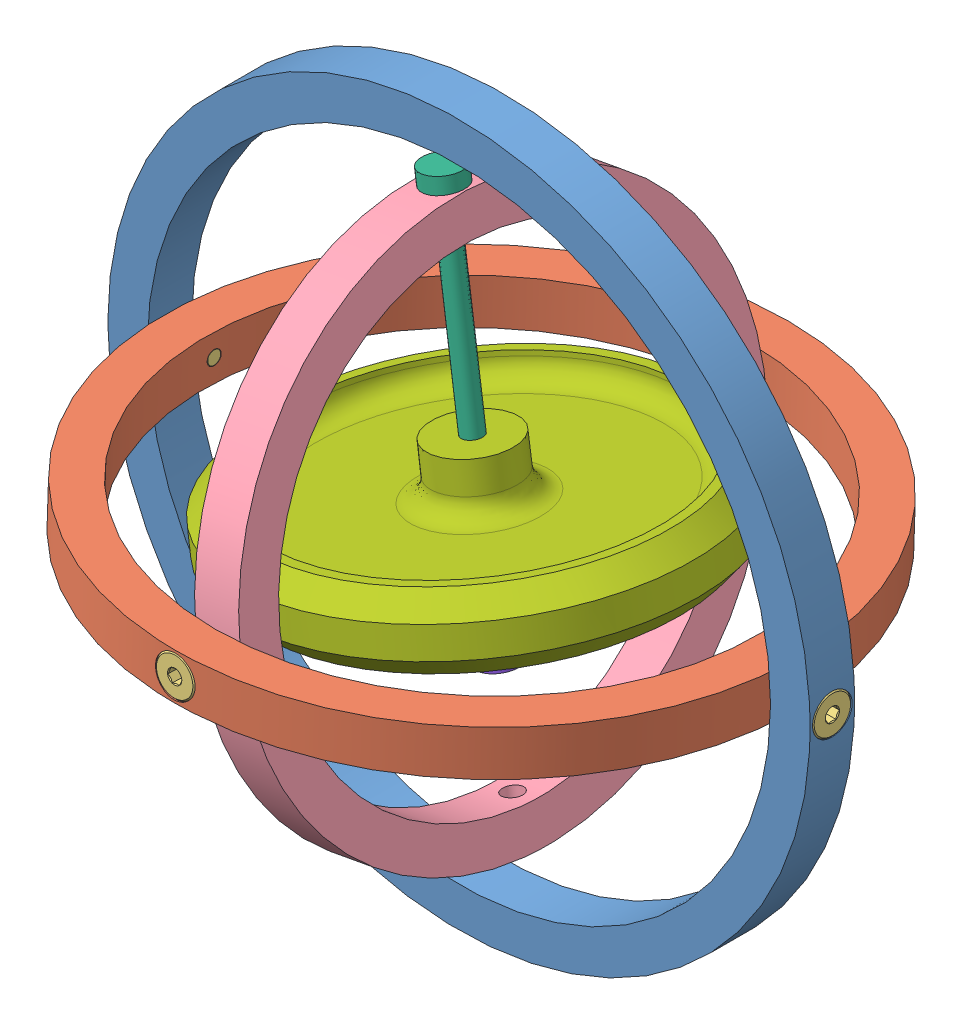
SolidWorks assembly Master Gyro Assembly, configuration Default. Lengths in mm.
Overall size (112.72 112.71 101.83).
15 component instances, 8 part files, 6 mates.
Components (placement in the parent):
- Outer Ring Assembly-1: Outer Ring Assembly [Default] at origin size (112.71 112.71 7.14)
  - Outer Ring-1: Outer Ring [Default] at origin size (112.71 112.71 7.14)
- Center Ring Assembly-1: Center Ring Assembly [Default] at (-0.0036 0 0) x (1 0 0) z (0 0.034637 0.9994) size (112.72 7.14 98.42)
  - Center Ring-1: Center Ring [Default] at origin size (98.42 7.14 98.42)
  - 95446A632_FRICTION-RESISTANT BRASS SHOULDER SCREW-1: 95446A632_FRICTION-RESISTANT BRASS SHOULDER SCREW [95446A632] at (56.3599 0 0) x (0 0.997776 0.06665) z (1 0 0) size (6.35 6.35 13.75)
  - 95446A632_FRICTION-RESISTANT BRASS SHOULDER SCREW-2: 95446A632_FRICTION-RESISTANT BRASS SHOULDER SCREW [95446A632] at (-56.3599 0 0) x (0 0.997776 -0.06665) z (-1 0 0) size (6.35 6.35 13.75)
- Inner Ring Assembly-1: Inner Ring Assembly [Default] at (-0.0036 0.0001 0.0036) x (0.17505 -0.983969 0.034102) z (0.98456 0.174945 -0.006063) size (86.52 98.43 83.7)
  - Inner Ring-1: Inner Ring [Default] at origin size (84.14 84.14 7.14)
  - 95446A632_FRICTION-RESISTANT BRASS SHOULDER SCREW-1: 95446A632_FRICTION-RESISTANT BRASS SHOULDER SCREW [95446A632] at (0 49.2161 0) x (1 0 0) z (0 1 0) size (6.35 6.35 13.75)
  - 95446A632_FRICTION-RESISTANT BRASS SHOULDER SCREW-2: 95446A632_FRICTION-RESISTANT BRASS SHOULDER SCREW [95446A632] at (0 -49.2161 0) x (-1 0 0) z (0 -1 0) size (6.35 6.35 13.75)
  - 57155K346_SS BALL BEARING-1: 57155K346_SS BALL BEARING [57155K346] at (-40.0844 0 0) x (0 0 -1) z (1 0 0) size (6.35 6.35 2.38)
  - 57155K346_SS BALL BEARING-2: 57155K346_SS BALL BEARING [57155K346] at (40.0844 0 0) x (0 0 -1) z (-1 0 0) size (6.35 6.35 2.38)
  - Gyro Shaft-1: Gyro Shaft [Default] at (-12.7 0 0) x (0 -0.953317 -0.301971) z (1 0 0) size (6.35 6.35 60.33)
  - Flywheel-1: Flywheel [Default] at (-0.4149 0 0) x (0 -0.301971 0.953317) z (0 0.953317 0.301971) size (66.67 19.05 66.67)
  - Shaft Cap Screw-1: Shaft Cap Screw [Default] at (16.129 0 0) x (0 -0.698146 0.715955) z (-1 0 0) size (6.35 6.35 8.38)
Mates (geometry in assembly coordinates):
- Concentric1: concentric anti-aligned: cylinder of ? through (22.225 0 0) axis (-1 0 0) radius 1.1906; cylinder of Center Ring Assembly-1/Center Ring-1 through (30.6089 0 0) axis (1 0 0) radius 1.1906
- Coincident1: coordinate: point of Outer Ring Assembly-1/Outer Ring-1
- Concentric2: concentric anti-aligned: cylinder of Outer Ring Assembly-1/Outer Ring-1 through (56.3562 0 0) axis (1 0 0) radius 1.5875; cylinder of Center Ring Assembly-1/95446A632_FRICTION-RESISTANT BRASS SHOULDER SCREW-1 through (42.8625 0 0) axis (-1 0 0) radius 1.5875
- Coincident2: coincident anti-aligned: plane of Outer Ring Assembly-1/Outer Ring-1 through (53.1812 1.5875 0) normal (1 0 0); plane of Center Ring Assembly-1/95446A632_FRICTION-RESISTANT BRASS SHOULDER SCREW-1 through (53.1812 0.1018 -3.1734) normal (-1 0 0)
- Concentric3: concentric anti-aligned: cylinder of Center Ring Assembly-1/Center Ring-1 through (-0.0036 -1.7046 -49.183) axis (0 -0.034637 -0.9994) radius 1.5875; cylinder of Inner Ring Assembly-1/95446A632_FRICTION-RESISTANT BRASS SHOULDER SCREW-1 through (-0.0036 -1.2372 -35.6973) axis (0 0.034637 0.9994) radius 1.5875
- Coincident3: coincident anti-aligned: plane of Center Ring Assembly-1/Center Ring-1 through (1.5839 -1.5946 -46.0099) normal (0 -0.034637 -0.9994); plane of Inner Ring Assembly-1/95446A632_FRICTION-RESISTANT BRASS SHOULDER SCREW-1 through (3.1223 -1.0391 -46.0291) normal (0 0.034637 0.9994)
